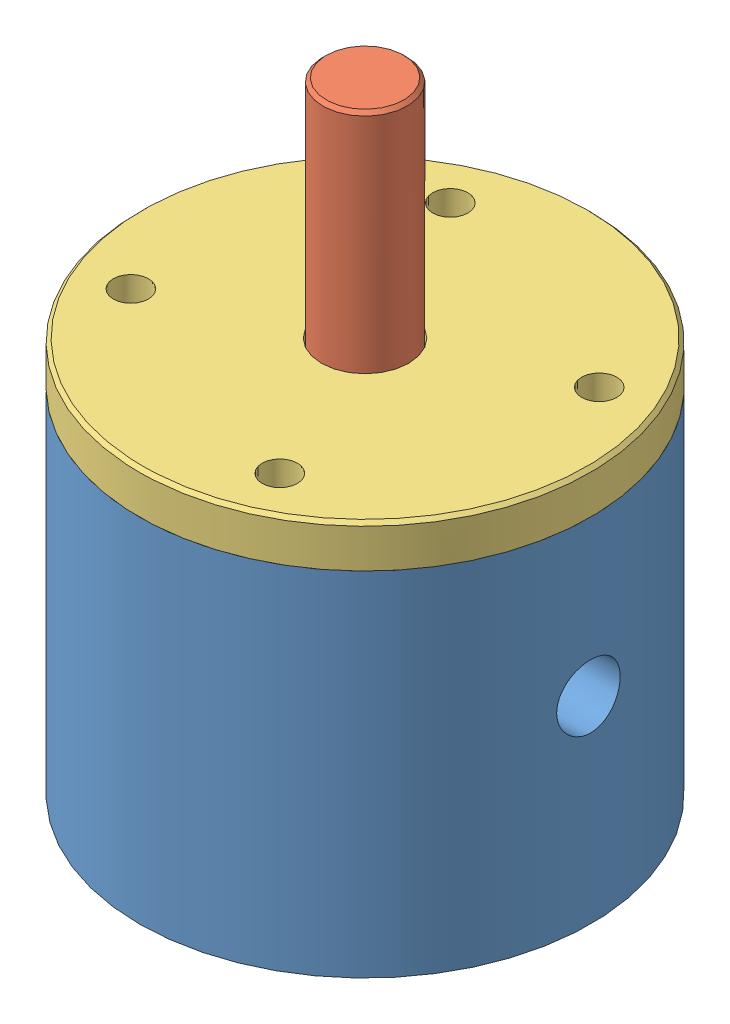
SolidWorks assembly Montagem_Shutter_v10, configuration Default. Lengths in mm.
Overall size (32 44.5 32).
3 component instances, 3 part files, 6 mates.
Components (placement in the parent):
- Sede_Inferior_v10-1: Sede_Inferior_v10 [Valor predeterminado<Como usinado>] at origin size (32 25 32)
- Desviador_v10-1: Desviador_v10 [Valor predeterminado] x (-0.998764 0 0.049699) z (-0.049699 0 -0.998764) size (16.34 44.5 16)
- Sede_superior_v10-1: Sede_superior_v10 [Valor predeterminado] at (0 12.5 0) size (32 4 32)
Mates (geometry in assembly coordinates):
- Coincident1: coordinate: point of Sede_Inferior_v10-1; point of assembly
- Concentric1: concentric aligned: cylinder of Sede_Inferior_v10-1 through (0 -14 0) axis (0 -1 0) radius 3; cylinder of Desviador_v10-1 through (0 0 0) axis (0 -1 0) radius 3
- Coincident2: coincident anti-aligned: plane of Sede_Inferior_v10-1 through (8 -10 0) normal (0 1 0); plane of Desviador_v10-1 through (-2.9963 -10 0.1491) normal (0 -1 0)
- Concêntrico1: concentric aligned: cylinder of Desviador_v10-1 through (0 0 0) axis (0 -1 0) radius 3; cylinder of Sede_superior_v10-1 through (0 12.5 0) axis (0 -1 0) radius 3.1
- Coincidente3: coincident anti-aligned: plane of Sede_superior_v10-1 through (9 11 0) normal (0 -1 0); plane of Sede_Inferior_v10-1 through (0 11 0) normal (0 1 0)
- Concêntrico4: concentric aligned: cylinder of Sede_Inferior_v10-1 through (5.2827 11 11.3288) axis (0 1 0) radius 1.25; cylinder of Sede_superior_v10-1 through (5.2827 14 11.3288) axis (0 1 0) radius 1.25
